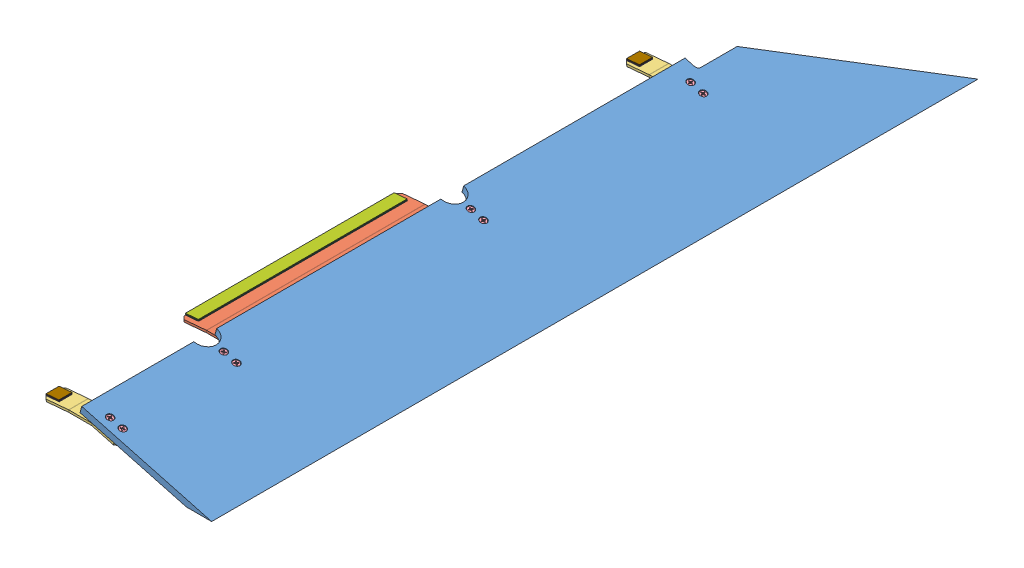
SolidWorks assembly GE-22016, configuration Default. Lengths in mm.
Overall size (328.85 67.77 1492.25).
32 component instances, 9 part files, 77 mates.
Components (placement in the parent):
- GE-22020-1: GE-22020 [Default] at origin size (256.21 67.77 1492.25)
- GE-22018-1: GE-22018 [Default] at (22.6565 49.2824 1011.2375) x (0 0 -1) z (1 0 0) size (504.82 17.25 144.58)
- GE-22019-1: GE-22019 [Default] at (22.6565 49.2824 1473.2) x (0 0 -1) z (1 0 0) size (38.1 17.25 144.58)
- GE-22019-2: GE-22019 [Default] at (22.6565 49.2824 342.9) x (0 0 -1) z (1 0 0) size (38.1 17.25 144.58)
- flat_phil_.25_20_1.25-1: flat_phil_.25_20_1.25 [Default] at (60.5885 53.5322 1473.2) x (0.933013 -0.25 -0.258819) z (0.258819 0.965926 0) size (12.12 12.12 31.75)
- flat_phil_.25_20_1.25-2: flat_phil_.25_20_1.25 [Default] at (85.1231 46.9582 1473.2) x (0.854154 -0.22887 -0.466946) z (0.258819 0.965926 0) size (12.12 12.12 31.75)
- flat_phil_.25_20_1.25-4: flat_phil_.25_20_1.25 [Default] at (60.5885 53.5322 1251.7437) x (0.72201 -0.193462 -0.664285) z (0.258819 0.965926 0) size (12.12 12.12 31.75)
- flat_phil_.25_20_1.25-6: flat_phil_.25_20_1.25 [Default] at (85.1231 46.9582 1251.7437) x (0.543088 -0.14552 -0.82697) z (0.258819 0.965926 0) size (12.12 12.12 31.75)
- flat_phil_.25_20_1.25-8: flat_phil_.25_20_1.25 [Default] at (60.5885 53.5322 770.7312) x (0.338851 -0.090795 -0.936449) z (0.258819 0.965926 0) size (12.12 12.12 31.75)
- flat_phil_.25_20_1.25-10: flat_phil_.25_20_1.25 [Default] at (85.1231 46.9582 770.7312) x (0.139431 -0.03736 -0.989527) z (0.258819 0.965926 0) size (12.12 12.12 31.75)
- flat_phil_.25_20_1.25-12: flat_phil_.25_20_1.25 [Default] at (60.5885 53.5322 342.9) x (-0.028036 0.007512 -0.999579) z (0.258819 0.965926 0) size (12.12 12.12 31.75)
- flat_phil_.25_20_1.25-14: flat_phil_.25_20_1.25 [Default] at (85.1231 46.9582 342.9) x (-0.146973 0.039381 -0.988356) z (0.258819 0.965926 0) size (12.12 12.12 31.75)
- nylock_.25_20-1: nylock_.25_20 [Default] at (57.4071 41.6589 1473.2) x (-0.780768 0.209206 -0.588756) z (-0.568695 0.152381 0.808311) size (11.11 7.94 12.83)
- nylock_.25_20-2: nylock_.25_20 [Default] at (81.9416 35.0849 1473.2) x (-0.8876 0.237832 -0.394464) z (-0.381023 0.102095 0.918912) size (11.11 7.94 12.83)
- nylock_.25_20-4: nylock_.25_20 [Default] at (57.4071 41.6589 1251.7437) x (-0.952842 0.255313 -0.164037) z (-0.158448 0.042456 0.986454) size (11.11 7.94 12.83)
- nylock_.25_20-6: nylock_.25_20 [Default] at (81.9416 35.0849 1251.7437) x (-0.96265 0.257941 0.082286) z (0.079482 -0.021297 0.996609) size (11.11 7.94 12.83)
- nylock_.25_20-8: nylock_.25_20 [Default] at (81.9416 35.0849 770.7312) x (-0.916572 0.245595 0.315561) z (0.304808 -0.081673 0.948905) size (11.11 7.94 12.83)
- nylock_.25_20-10: nylock_.25_20 [Default] at (57.4071 41.6589 770.7312) x (-0.831142 0.222704 0.509516) z (0.492155 -0.131872 0.860461) size (11.11 7.94 12.83)
- nylock_.25_20-12: nylock_.25_20 [Default] at (81.9416 35.0849 342.9) x (-0.733461 0.19653 0.650701) z (0.628529 -0.168414 0.759334) size (11.11 7.94 12.83)
- nylock_.25_20-14: nylock_.25_20 [Default] at (57.4071 41.6589 342.9) x (-0.650289 0.174245 0.739434) z (0.714238 -0.19138 0.673229) size (11.11 7.94 12.83)
- Hook_1_16-1: Hook_1_16 [Default] at (35.4452 43.4277 1214.4375) x (0 0 -1) z (1 0 0) size (406.4 1.59 25.4)
- Hook_1_16-2: Hook_1_16 [Default] at (-50.1321 44.8749 808.0375) x (0 0 1) z (-0.996195 -0.087156 0) size (406.4 1.59 25.4)
- Loop_1_16-1: Loop_1_16 [Default] at (10.0452 41.8402 808.0375) x (0 0 1) z (-1 0 0) size (406.4 1.59 25.4)
- Loop_1_16-2: Loop_1_16 [Default] at (-50.2704 46.4564 808.0375) x (0 0 1) z (-0.996195 -0.087156 0) size (406.4 1.59 25.4)
- Hook_1_1-1: Hook_1_1 [Default] at (-50.1321 44.8749 355.6) x (0.996195 0.087156 0) z (0 0 1) size (25.4 1.59 25.4)
- Hook_1_1-2: Hook_1_1 [Default] at (-50.1321 44.8749 1485.9) x (0.996195 0.087156 0) z (0 0 1) size (25.4 1.59 25.4)
- Hook_1_1-3: Hook_1_1 [Default] at (10.0452 43.4277 1485.9) size (25.4 1.59 25.4)
- Hook_1_1-4: Hook_1_1 [Default] at (10.0452 43.4277 355.6) size (25.4 1.59 25.4)
- Loop_1_1-1: Loop_1_1 [Default] at (10.0452 41.8402 355.6) size (25.4 1.59 25.4)
- Loop_1_1-2: Loop_1_1 [Default] at (-50.2704 46.4564 355.6) x (0.996195 0.087156 0) z (0 0 1) size (25.4 1.59 25.4)
- Loop_1_1-3: Loop_1_1 [Default] at (-50.2704 46.4564 1485.9) x (0.996195 0.087156 0) z (0 0 1) size (25.4 1.59 25.4)
- Loop_1_1-4: Loop_1_1 [Default] at (10.0452 41.8402 1485.9) size (25.4 1.59 25.4)
Mates (geometry in assembly coordinates):
- Coincident1: coincident anti-aligned: plane of GE-22020-1 through (22.225 55.5037 1492.25) normal (-0.258819 -0.965926 0); plane of BracketRampMid_v5-1 through (24.1829 54.9791 1011.2375) normal (0.258819 0.965926 0)
- Concentric1: concentric aligned: cylinder of GE-22020-1 through (61.7986 58.048 1251.7437) axis (0.258819 0.965926 0) radius 3.5712; cylinder of BracketRampMid_v5-1 through (58.5115 45.7807 1251.7437) axis (0.258819 0.965926 0) radius 3.3735
- Concentric2: concentric aligned: cylinder of GE-22020-1 through (86.3331 51.474 1251.7437) axis (0.258819 0.965926 0) radius 3.5712; cylinder of BracketRampMid_v5-1 through (83.0461 39.2067 1251.7437) axis (0.258819 0.965926 0) radius 3.3735
- Coincident2: coincident anti-aligned: plane of GE-22020-1 through (22.225 55.5037 1492.25) normal (-0.258819 -0.965926 0); plane of BracketRampEdge_v5-1 through (24.1829 54.9791 1473.2) normal (0.258819 0.965926 0)
- Concentric3: concentric aligned: cylinder of GE-22020-1 through (61.7986 58.048 1473.2) axis (0.258819 0.965926 0) radius 3.5712; cylinder of BracketRampEdge_v5-1 through (58.5115 45.7807 1473.2) axis (0.258819 0.965926 0) radius 3.3735
- Concentric4: concentric aligned: cylinder of GE-22020-1 through (86.3331 51.474 1473.2) axis (0.258819 0.965926 0) radius 3.5712; cylinder of BracketRampEdge_v5-1 through (83.0461 39.2067 1473.2) axis (0.258819 0.965926 0) radius 3.3735
- Coincident3: coincident anti-aligned: plane of GE-22020-1 through (22.225 55.5037 1492.25) normal (-0.258819 -0.965926 0); plane of BracketRampEdge_v5-2 through (24.1829 54.9791 342.9) normal (0.258819 0.965926 0)
- Concentric5: concentric aligned: cylinder of GE-22020-1 through (61.7986 58.048 342.9) axis (0.258819 0.965926 0) radius 3.5712; cylinder of BracketRampEdge_v5-2 through (58.5115 45.7807 342.9) axis (0.258819 0.965926 0) radius 3.3735
- Concentric6: concentric aligned: cylinder of GE-22020-1 through (86.3331 51.474 342.9) axis (0.258819 0.965926 0) radius 3.5712; cylinder of BracketRampEdge_v5-2 through (83.0461 39.2067 342.9) axis (0.258819 0.965926 0) radius 3.3735
- Concentric7: concentric aligned: cylinder of GE-22020-1 through (61.7986 58.048 1473.2) axis (0.258819 0.965926 0) radius 3.5712; cylinder of flat_phil_.25_20_1.25-1 through (61.5944 57.2859 1473.2) axis (0.258819 0.965926 0) radius 3.175
- Coincident4: coincident aligned: cone of GE-22020-1 through (61.7986 58.048 1473.2) axis (-0.258819 -0.965926 0); cone of flat_phil_.25_20_1.25-1 through (61.5944 57.2859 1473.2) axis (-0.258819 -0.965926 0)
- Concentric8: concentric aligned: cylinder of GE-22020-1 through (86.3331 51.474 1473.2) axis (0.258819 0.965926 0) radius 3.5712; cylinder of flat_phil_.25_20_1.25-2 through (86.1289 50.7119 1473.2) axis (0.258819 0.965926 0) radius 3.175
- Coincident5: coincident aligned: cone of GE-22020-1 through (86.3331 51.474 1473.2) axis (-0.258819 -0.965926 0); cone of flat_phil_.25_20_1.25-2 through (86.1289 50.7119 1473.2) axis (-0.258819 -0.965926 0)
- Concentric9: concentric aligned: cylinder of GE-22020-1 through (61.7986 58.048 1251.7437) axis (0.258819 0.965926 0) radius 3.5712; cylinder of flat_phil_.25_20_1.25-4 through (61.5944 57.2859 1251.7437) axis (0.258819 0.965926 0) radius 3.175
- Coincident6: coincident aligned: cone of GE-22020-1 through (61.7986 58.048 1251.7437) axis (-0.258819 -0.965926 0); cone of flat_phil_.25_20_1.25-4 through (61.5944 57.2859 1251.7437) axis (-0.258819 -0.965926 0)
- Concentric10: concentric aligned: cylinder of GE-22020-1 through (86.3331 51.474 1251.7437) axis (0.258819 0.965926 0) radius 3.5712; cylinder of flat_phil_.25_20_1.25-6 through (86.1289 50.7119 1251.7437) axis (0.258819 0.965926 0) radius 3.175
- Coincident7: coincident aligned: cone of GE-22020-1 through (86.3331 51.474 1251.7437) axis (-0.258819 -0.965926 0); cone of flat_phil_.25_20_1.25-6 through (86.1289 50.7119 1251.7437) axis (-0.258819 -0.965926 0)
- Concentric11: concentric aligned: cylinder of GE-22020-1 through (61.7986 58.048 770.7312) axis (0.258819 0.965926 0) radius 3.5712; cylinder of flat_phil_.25_20_1.25-8 through (61.5944 57.2859 770.7312) axis (0.258819 0.965926 0) radius 3.175
- Coincident8: coincident aligned: cone of GE-22020-1 through (61.7986 58.048 770.7312) axis (-0.258819 -0.965926 0); cone of flat_phil_.25_20_1.25-8 through (61.5944 57.2859 770.7312) axis (-0.258819 -0.965926 0)
- Concentric12: concentric aligned: cylinder of GE-22020-1 through (86.3331 51.474 770.7312) axis (0.258819 0.965926 0) radius 3.5712; cylinder of flat_phil_.25_20_1.25-10 through (86.1289 50.7119 770.7312) axis (0.258819 0.965926 0) radius 3.175
- Coincident9: coincident aligned: cone of GE-22020-1 through (86.3331 51.474 770.7312) axis (-0.258819 -0.965926 0); cone of flat_phil_.25_20_1.25-10 through (86.1289 50.7119 770.7312) axis (-0.258819 -0.965926 0)
- Concentric13: concentric aligned: cylinder of GE-22020-1 through (61.7986 58.048 342.9) axis (0.258819 0.965926 0) radius 3.5712; cylinder of flat_phil_.25_20_1.25-12 through (61.5944 57.2859 342.9) axis (0.258819 0.965926 0) radius 3.175
- Coincident10: coincident aligned: cone of GE-22020-1 through (61.7986 58.048 342.9) axis (-0.258819 -0.965926 0); cone of flat_phil_.25_20_1.25-12 through (61.5944 57.2859 342.9) axis (-0.258819 -0.965926 0)
- Concentric14: concentric aligned: cylinder of GE-22020-1 through (86.3331 51.474 342.9) axis (0.258819 0.965926 0) radius 3.5712; cylinder of flat_phil_.25_20_1.25-14 through (86.1289 50.7119 342.9) axis (0.258819 0.965926 0) radius 3.175
- Coincident11: coincident aligned: cone of GE-22020-1 through (86.3331 51.474 342.9) axis (-0.258819 -0.965926 0); cone of flat_phil_.25_20_1.25-14 through (86.1289 50.7119 342.9) axis (-0.258819 -0.965926 0)
- Concentric15: concentric anti-aligned: cylinder of flat_phil_.25_20_1.25-1 through (61.5944 57.2859 1473.2) axis (0.258819 0.965926 0) radius 3.175; cylinder of nylock_.25_20-1 through (57.4071 41.6589 1473.2) axis (-0.258819 -0.965926 0) radius 3.175
- Coincident12: coincident anti-aligned: plane of GE-22019-1 through (23.0784 50.8573 1473.2) normal (-0.258819 -0.965926 0); plane of nylock_.25_20-1 through (57.4071 41.6589 1473.2) normal (0.258819 0.965926 0)
- Concentric16: concentric anti-aligned: cylinder of flat_phil_.25_20_1.25-2 through (86.1289 50.7119 1473.2) axis (0.258819 0.965926 0) radius 3.175; cylinder of nylock_.25_20-2 through (81.9416 35.0849 1473.2) axis (-0.258819 -0.965926 0) radius 3.175
- Coincident13: coincident anti-aligned: plane of GE-22019-1 through (23.0784 50.8573 1473.2) normal (-0.258819 -0.965926 0); plane of nylock_.25_20-2 through (81.9416 35.0849 1473.2) normal (0.258819 0.965926 0)
- Concentric17: concentric anti-aligned: cylinder of flat_phil_.25_20_1.25-4 through (61.5944 57.2859 1251.7437) axis (0.258819 0.965926 0) radius 3.175; cylinder of nylock_.25_20-4 through (57.4071 41.6589 1251.7437) axis (-0.258819 -0.965926 0) radius 3.175
- Coincident14: coincident anti-aligned: plane of GE-22018-1 through (23.0784 50.8573 1011.2375) normal (-0.258819 -0.965926 0); plane of nylock_.25_20-4 through (57.4071 41.6589 1251.7437) normal (0.258819 0.965926 0)
- Concentric18: concentric anti-aligned: cylinder of flat_phil_.25_20_1.25-6 through (86.1289 50.7119 1251.7437) axis (0.258819 0.965926 0) radius 3.175; cylinder of nylock_.25_20-6 through (81.9416 35.0849 1251.7437) axis (-0.258819 -0.965926 0) radius 3.175
- Coincident15: coincident anti-aligned: plane of GE-22018-1 through (23.0784 50.8573 1011.2375) normal (-0.258819 -0.965926 0); plane of nylock_.25_20-6 through (81.9416 35.0849 1251.7437) normal (0.258819 0.965926 0)
- Concentric19: concentric anti-aligned: cylinder of flat_phil_.25_20_1.25-10 through (86.1289 50.7119 770.7312) axis (0.258819 0.965926 0) radius 3.175; cylinder of nylock_.25_20-8 through (81.9416 35.0849 770.7312) axis (-0.258819 -0.965926 0) radius 3.175
- Coincident16: coincident anti-aligned: plane of GE-22018-1 through (23.0784 50.8573 1011.2375) normal (-0.258819 -0.965926 0); plane of nylock_.25_20-8 through (81.9416 35.0849 770.7312) normal (0.258819 0.965926 0)
- Concentric20: concentric anti-aligned: cylinder of flat_phil_.25_20_1.25-8 through (61.5944 57.2859 770.7312) axis (0.258819 0.965926 0) radius 3.175; cylinder of nylock_.25_20-10 through (57.4071 41.6589 770.7312) axis (-0.258819 -0.965926 0) radius 3.175
- Coincident17: coincident anti-aligned: plane of GE-22018-1 through (23.0784 50.8573 1011.2375) normal (-0.258819 -0.965926 0); plane of nylock_.25_20-10 through (57.4071 41.6589 770.7312) normal (0.258819 0.965926 0)
- Concentric21: concentric anti-aligned: cylinder of flat_phil_.25_20_1.25-14 through (86.1289 50.7119 342.9) axis (0.258819 0.965926 0) radius 3.175; cylinder of nylock_.25_20-12 through (81.9416 35.0849 342.9) axis (-0.258819 -0.965926 0) radius 3.175
- Coincident18: coincident anti-aligned: plane of GE-22019-2 through (23.0784 50.8573 342.9) normal (-0.258819 -0.965926 0); plane of nylock_.25_20-12 through (81.9416 35.0849 342.9) normal (0.258819 0.965926 0)
- Concentric22: concentric anti-aligned: cylinder of flat_phil_.25_20_1.25-12 through (61.5944 57.2859 342.9) axis (0.258819 0.965926 0) radius 3.175; cylinder of nylock_.25_20-14 through (57.4071 41.6589 342.9) axis (-0.258819 -0.965926 0) radius 3.175
- Coincident19: coincident anti-aligned: plane of GE-22019-2 through (23.0784 50.8573 342.9) normal (-0.258819 -0.965926 0); plane of nylock_.25_20-14 through (57.4071 41.6589 342.9) normal (0.258819 0.965926 0)
- Coincident20: coincident anti-aligned: plane of GE-22018-1 through (22.6565 45.0152 1011.2375) normal (0 -1 0); plane of Hook_1_16-1 through (35.4452 45.0152 1214.4375) normal (0 1 0)
- Distance1: distance = 9.525 mm aligned: plane of Hook_1_16-1 through (35.4452 45.0152 1214.4375) normal (0 0 1); plane of GE-22018-1 through (0.4315 45.0152 1223.9625) normal (0 0 1)
- Distance2: distance = 9.525 mm: plane of Hook_1_16-1 through (10.0452 45.0152 1214.4375) normal (-1 0 0); line of GE-22018-1 through (0.5202 45.0152 798.5125) axis (0 0 1)
- Coincident23: coincident anti-aligned: plane of GE-22018-1 through (22.4862 51.2282 1011.2375) normal (-0.087156 0.996195 0); plane of Hook_1_16-2 through (-50.1321 44.8749 808.0375) normal (0.087156 -0.996195 0)
- Coincident24: coincident aligned: plane of GE-22018-1 through (-50.1321 44.8749 1223.9625) normal (-0.996195 -0.087156 0); plane of Hook_1_16-2 through (-50.2704 46.4564 808.0375) normal (-0.996195 -0.087156 0)
- Distance3: distance = 9.525 mm aligned: plane of GE-22018-1 through (-50.1321 44.8749 1223.9625) normal (0 0 1); plane of Hook_1_16-2 through (-50.2704 46.4564 1214.4375) normal (0 0 1)
- Coincident25: coincident anti-aligned: plane of Hook_1_16-1 through (35.4452 43.4277 1214.4375) normal (0 -1 0); plane of Loop_1_16-1 through (10.0452 43.4277 808.0375) normal (0 1 0)
- Coincident26: coincident aligned: plane of Hook_1_16-1 through (10.0452 45.0152 1214.4375) normal (-1 0 0); plane of Loop_1_16-1 through (10.0452 43.4277 808.0375) normal (-1 0 0)
- Coincident27: coincident aligned: plane of Hook_1_16-1 through (35.4452 45.0152 808.0375) normal (0 0 -1); plane of Loop_1_16-1 through (10.0452 43.4277 808.0375) normal (0 0 -1)
- Coincident28: coincident anti-aligned: plane of Hook_1_16-2 through (-50.2704 46.4564 808.0375) normal (-0.087156 0.996195 0); plane of Loop_1_16-2 through (-50.2704 46.4564 808.0375) normal (0.087156 -0.996195 0)
- Coincident29: coincident aligned: plane of Hook_1_16-2 through (-50.2704 46.4564 808.0375) normal (-0.996195 -0.087156 0); plane of Loop_1_16-2 through (-50.4088 48.0378 808.0375) normal (-0.996195 -0.087156 0)
- Coincident30: coincident aligned: plane of Hook_1_16-2 through (-50.2704 46.4564 808.0375) normal (0 0 -1); plane of Loop_1_16-2 through (-50.4088 48.0378 808.0375) normal (0 0 -1)
- Coincident31: coincident anti-aligned: plane of GE-22019-2 through (22.4862 51.2282 342.9) normal (-0.087156 0.996195 0); plane of Hook_1_1-1 through (-50.1321 44.8749 355.6) normal (0.087156 -0.996195 0)
- Coincident32: coincident aligned: plane of GE-22019-2 through (-50.1321 44.8749 361.95) normal (-0.996195 -0.087156 0); plane of Hook_1_1-1 through (-50.2704 46.4564 355.6) normal (-0.996195 -0.087156 0)
- Coincident33: coincident: line of GE-22019-2 through (-49.7602 40.624 355.6) axis (-0.087156 0.996195 0); plane of Hook_1_1-1 through (-50.2704 46.4564 355.6) normal (0 0 1)
- Coincident34: coincident anti-aligned: plane of GE-22019-2 through (22.6565 45.0152 342.9) normal (0 -1 0); plane of Hook_1_1-4 through (10.0452 45.0152 355.6) normal (0 1 0)
- Coincident35: coincident aligned: plane of Hook_1_1-1 through (-50.2704 46.4564 355.6) normal (0 0 1); plane of Hook_1_1-4 through (10.0452 45.0152 355.6) normal (0 0 1)
- Coincident36: coincident aligned: plane of Hook_1_16-1 through (10.0452 45.0152 1214.4375) normal (-1 0 0); plane of Hook_1_1-4 through (10.0452 45.0152 355.6) normal (-1 0 0)
- Coincident38: coincident anti-aligned: plane of GE-22019-1 through (22.6565 45.0152 1473.2) normal (0 -1 0); plane of Hook_1_1-3 through (10.0452 45.0152 1485.9) normal (0 1 0)
- Coincident39: coincident aligned: plane of Hook_1_16-1 through (10.0452 45.0152 1214.4375) normal (-1 0 0); plane of Hook_1_1-3 through (10.0452 45.0152 1485.9) normal (-1 0 0)
- Coincident40: coincident anti-aligned: plane of GE-22019-1 through (22.4862 51.2282 1473.2) normal (-0.087156 0.996195 0); plane of Hook_1_1-2 through (-50.1321 44.8749 1485.9) normal (0.087156 -0.996195 0)
- Coincident41: coincident aligned: plane of GE-22019-1 through (-50.1321 44.8749 1492.25) normal (-0.996195 -0.087156 0); plane of Hook_1_1-2 through (-50.2704 46.4564 1485.9) normal (-0.996195 -0.087156 0)
- Coincident42: coincident: line of GE-22019-1 through (-49.7602 40.624 1485.9) axis (-0.087156 0.996195 0); plane of Hook_1_1-2 through (-50.2704 46.4564 1485.9) normal (0 0 1)
- Coincident43: coincident aligned: plane of Hook_1_1-2 through (-50.2704 46.4564 1485.9) normal (0 0 1); plane of Hook_1_1-3 through (10.0452 45.0152 1485.9) normal (0 0 1)
- Coincident44: coincident anti-aligned: plane of Hook_1_1-4 through (10.0452 43.4277 355.6) normal (0 -1 0); plane of Loop_1_1-1 through (10.0452 43.4277 355.6) normal (0 1 0)
- Coincident45: coincident aligned: plane of Hook_1_1-4 through (10.0452 45.0152 355.6) normal (0 0 1); plane of Loop_1_1-1 through (10.0452 43.4277 355.6) normal (0 0 1)
- Coincident46: coincident aligned: plane of Hook_1_1-4 through (10.0452 45.0152 355.6) normal (-1 0 0); plane of Loop_1_1-1 through (10.0452 43.4277 355.6) normal (-1 0 0)
- Coincident47: coincident anti-aligned: plane of Hook_1_1-1 through (-50.2704 46.4564 355.6) normal (-0.087156 0.996195 0); plane of Loop_1_1-2 through (-50.2704 46.4564 355.6) normal (0.087156 -0.996195 0)
- Coincident48: coincident aligned: plane of Hook_1_1-1 through (-50.2704 46.4564 355.6) normal (0 0 1); plane of Loop_1_1-2 through (-50.4088 48.0378 355.6) normal (0 0 1)
- Coincident49: coincident aligned: plane of Hook_1_1-1 through (-50.2704 46.4564 355.6) normal (-0.996195 -0.087156 0); plane of Loop_1_1-2 through (-50.4088 48.0378 355.6) normal (-0.996195 -0.087156 0)
- Coincident50: coincident anti-aligned: plane of Hook_1_1-2 through (-50.2704 46.4564 1485.9) normal (-0.087156 0.996195 0); plane of Loop_1_1-3 through (-50.2704 46.4564 1485.9) normal (0.087156 -0.996195 0)
- Coincident51: coincident aligned: plane of Hook_1_1-2 through (-50.2704 46.4564 1485.9) normal (0 0 1); plane of Loop_1_1-3 through (-50.4088 48.0378 1485.9) normal (0 0 1)
- Coincident52: coincident aligned: plane of Hook_1_1-2 through (-50.2704 46.4564 1485.9) normal (-0.996195 -0.087156 0); plane of Loop_1_1-3 through (-50.4088 48.0378 1485.9) normal (-0.996195 -0.087156 0)
- Coincident53: coincident anti-aligned: plane of Hook_1_1-3 through (10.0452 43.4277 1485.9) normal (0 -1 0); plane of Loop_1_1-4 through (10.0452 43.4277 1485.9) normal (0 1 0)
- Coincident54: coincident aligned: plane of Hook_1_1-3 through (10.0452 45.0152 1485.9) normal (0 0 1); plane of Loop_1_1-4 through (10.0452 43.4277 1485.9) normal (0 0 1)
- Coincident55: coincident aligned: plane of Hook_1_1-3 through (10.0452 45.0152 1485.9) normal (-1 0 0); plane of Loop_1_1-4 through (10.0452 43.4277 1485.9) normal (-1 0 0)
